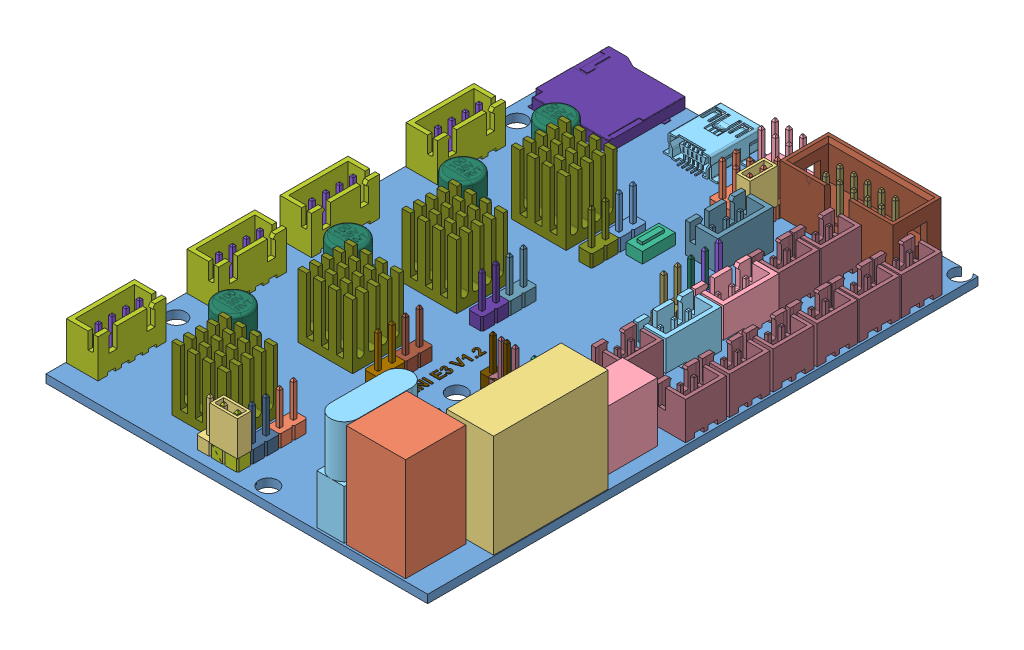
SolidWorks assembly BTT SKR MINI E3 V1.2 - 2020 DR.Phil3D v1.step, configuration Default. Lengths in mm.
Overall size (69.7 22.28 101.21).
95 component instances, 41 part files, 0 mates.
Components (placement in the parent):
- SKR Mini E3 1.2-1: SKR Mini E3 1.2 [SKR Mini E3 1.2] at (0.4313 -1.6126 -0.8701) size (69.7 20.32 100.5)
  - PCB-1: PCB [PCB] at origin size (69.7 1.5 100.5)
  - Power IN-1: Power IN [Power IN] at (-14.6583 0 -3.0665) size (10.79 18.82 11)
  - Power & Bed -1: Power & Bed  [Power & Bed ] at (-15.6583 0 -3.0665) size (8.58 18.82 20.9)
  - E0-1: E0 [E0] at (-15.6583 0 -3.0665) size (6.36 10.82 10)
  - Fuse-1: Fuse [Fuse] at (-14.6583 0 -3.0665) size (5 18.48 14.84)
  - Reset-1: Reset [Reset] at (-4.0633 0 9.9288) size (3 2.5 6)
- 4 pin Header-1: 4 pin Header [4 pin Header] at (-25.3481 -5.4688 -25.9996) x (0 0 1) z (-1 0 0) size (12.4 10.4 5.75)
  - B4B-XH-A (BODY)-1: B4B-XH-A (BODY) [B4B-XH-A (BODY)] at (1.9192 5.3562 13.8157) size (12.4 7 5.75)
  - B4B-XH-A (PIN)-1: B4B-XH-A (PIN) [B4B-XH-A (PIN)] at (5.6692 12.3562 13.2907) x (-1 0 0) z (0 0 1) size (0.64 10.4 0.64)
  - B4B-XH-A (PIN)-2: B4B-XH-A (PIN) [B4B-XH-A (PIN)] at (3.1692 12.3562 13.2907) x (-1 0 0) z (0 0 1) size (0.64 10.4 0.64)
  - B4B-XH-A (PIN)-3: B4B-XH-A (PIN) [B4B-XH-A (PIN)] at (0.6692 12.3562 13.2907) x (-1 0 0) z (0 0 1) size (0.64 10.4 0.64)
  - B4B-XH-A (PIN)-4: B4B-XH-A (PIN) [B4B-XH-A (PIN)] at (-1.8308 12.3562 13.2907) x (-1 0 0) z (0 0 1) size (0.64 10.4 0.64)
- 4 pin Header_1-1: 4 pin Header_1 [4 pin Header_1] at (-25.3481 -5.4688 -2.9996) x (0 0 1) z (-1 0 0) size (12.4 10.4 5.75)
  - B4B-XH-A (BODY)-1: B4B-XH-A (BODY) [B4B-XH-A (BODY)] at (1.9192 5.3562 13.8157) size (12.4 7 5.75)
  - B4B-XH-A (PIN)-1: B4B-XH-A (PIN) [B4B-XH-A (PIN)] at (5.6692 12.3562 13.2907) x (-1 0 0) z (0 0 1) size (0.64 10.4 0.64)
  - B4B-XH-A (PIN)-2: B4B-XH-A (PIN) [B4B-XH-A (PIN)] at (3.1692 12.3562 13.2907) x (-1 0 0) z (0 0 1) size (0.64 10.4 0.64)
  - B4B-XH-A (PIN)-3: B4B-XH-A (PIN) [B4B-XH-A (PIN)] at (0.6692 12.3562 13.2907) x (-1 0 0) z (0 0 1) size (0.64 10.4 0.64)
  - B4B-XH-A (PIN)-4: B4B-XH-A (PIN) [B4B-XH-A (PIN)] at (-1.8308 12.3562 13.2907) x (-1 0 0) z (0 0 1) size (0.64 10.4 0.64)
- 4 pin Header_2-1: 4 pin Header_2 [4 pin Header_2] at (-25.3481 -5.4688 14.0004) x (0 0 1) z (-1 0 0) size (12.4 10.4 5.75)
  - B4B-XH-A (BODY)-1: B4B-XH-A (BODY) [B4B-XH-A (BODY)] at (1.9192 5.3562 13.8157) size (12.4 7 5.75)
  - B4B-XH-A (PIN)-1: B4B-XH-A (PIN) [B4B-XH-A (PIN)] at (5.6692 12.3562 13.2907) x (-1 0 0) z (0 0 1) size (0.64 10.4 0.64)
  - B4B-XH-A (PIN)-2: B4B-XH-A (PIN) [B4B-XH-A (PIN)] at (3.1692 12.3562 13.2907) x (-1 0 0) z (0 0 1) size (0.64 10.4 0.64)
  - B4B-XH-A (PIN)-3: B4B-XH-A (PIN) [B4B-XH-A (PIN)] at (0.6692 12.3562 13.2907) x (-1 0 0) z (0 0 1) size (0.64 10.4 0.64)
  - B4B-XH-A (PIN)-4: B4B-XH-A (PIN) [B4B-XH-A (PIN)] at (-1.8308 12.3562 13.2907) x (-1 0 0) z (0 0 1) size (0.64 10.4 0.64)
- 4 pin Header_3-1: 4 pin Header_3 [4 pin Header_3] at (-25.3481 -5.4688 36.0004) x (0 0 1) z (-1 0 0) size (12.4 10.4 5.75)
  - B4B-XH-A (BODY)-1: B4B-XH-A (BODY) [B4B-XH-A (BODY)] at (1.9192 5.3562 13.8157) size (12.4 7 5.75)
  - B4B-XH-A (PIN)-1: B4B-XH-A (PIN) [B4B-XH-A (PIN)] at (5.6692 12.3562 13.2907) x (-1 0 0) z (0 0 1) size (0.64 10.4 0.64)
  - B4B-XH-A (PIN)-2: B4B-XH-A (PIN) [B4B-XH-A (PIN)] at (3.1692 12.3562 13.2907) x (-1 0 0) z (0 0 1) size (0.64 10.4 0.64)
  - B4B-XH-A (PIN)-3: B4B-XH-A (PIN) [B4B-XH-A (PIN)] at (0.6692 12.3562 13.2907) x (-1 0 0) z (0 0 1) size (0.64 10.4 0.64)
  - B4B-XH-A (PIN)-4: B4B-XH-A (PIN) [B4B-XH-A (PIN)] at (-1.8308 12.3562 13.2907) x (-1 0 0) z (0 0 1) size (0.64 10.4 0.64)
- 2 Pin connector (13)-1: 2 Pin connector (13) [2 Pin connector (13)] at (10.6557 -0.1126 28.8793) x (0 0 -1) z (1 0 0) size (5.08 11.94 2.54)
  - Component52-1: Component52 [Component52] at origin size (5.08 11.94 2.54)
- 2 Pin connector (19)-1: 2 Pin connector (19) [2 Pin connector (19)] at (8.1557 -0.1126 28.8793) x (0 0 -1) z (1 0 0) size (5.08 11.94 2.54)
  - Component53-1: Component53 [Component53] at origin size (5.08 11.94 2.54)
- DS1013-10SSiB v1-1: DS1013-10SSiB v1 [DS1013-10SSiB v1] at (5.7052 0 -46.8226) x (1 0 0) z (0 1 0) size (20.6 9.1 12.4)
  - body-1: body [body] at origin size (20.6 9.1 9.3)
  - pin-1: pin [pin] at origin size (0.64 0.64 11.5)
  - pin-2: pin [pin] at (2.54 0 0) size (0.64 0.64 11.5)
  - pin-3: pin [pin] at (5.08 0 0) size (0.64 0.64 11.5)
  - pin-4: pin [pin] at (7.62 0 0) size (0.64 0.64 11.5)
  - pin-5: pin [pin] at (0 2.54 0) size (0.64 0.64 11.5)
  - pin-6: pin [pin] at (2.54 2.54 0) size (0.64 0.64 11.5)
  - pin-7: pin [pin] at (5.08 2.54 0) size (0.64 0.64 11.5)
  - pin-8: pin [pin] at (7.62 2.54 0) size (0.64 0.64 11.5)
  - pin-9: pin [pin] at (10.16 0 0) size (0.64 0.64 11.5)
  - pin-10: pin [pin] at (10.16 2.54 0) size (0.64 0.64 11.5)
- JST 2pin.step-1: JST 2pin.step [Default] at (9.9082 -0.1126 -7.1947) x (-1 0 0) z (0 0 -1) size (5.73 10.3 7.43)
- Header 3 pin.step-1: Header 3 pin.step [Default] at (1.8482 -0.1126 -33.0477) x (0 0 1) z (-1 0 0) size (10.16 7.2 5.9)
- 100uF 35V 6.3x7.step-1: 100uF 35V 6.3x7.step [Default] at (-28.7944 0.8874 26.9674) x (-1 0 0) z (0 0 -1) size (6.66 7.76 7.2)
- TMC 2209 Heatsink.step-1: TMC 2209 Heatsink.step [Default] at (-21.6787 1.8374 38.0799) x (1 0 0) z (0 1 0) size (9.98 9.3 11.65)
- sdreader.step-1: sdreader.step [Default] at (-33.9687 -1.5126 -38.3866) x (0 0 1) z (0 1 0) size (15 16 2)
- Component14.step-1: Component14.step [Default] at origin size (1.85 0.1 25.79)
- Component15.step-1: Component15.step [Default] at origin size (0.73 0.1 6.6)
- 2 Pin connector.step-1: 2 Pin connector.step [Default] at (-0.9803 -0.3666 -42.1218) x (0 0 1) z (-1 0 0) size (5.08 11.94 2.54)
- Jumper.step-1: Jumper.step [Default] at (-15.4835 0 -3.6239) size (2.55 6.35 5.06)
- Header 3 pin (1).step-1: Header 3 pin (1).step [Default] at (12.9215 -0.1126 -22.9838) x (0 0 1) z (-1 0 0) size (10.16 7.2 5.9)
- Header 3 pin (2).step-1: Header 3 pin (2).step [Default] at (12.9215 -0.1126 -12.4838) x (0 0 1) z (-1 0 0) size (10.16 7.2 5.9)
- 100uF 35V 6.3x7.step-2: 100uF 35V 6.3x7.step [Default] at (-28.7944 0.8874 5.9674) x (-1 0 0) z (0 0 -1) size (6.66 7.76 7.2)
- TMC 2209 Heatsink.step-2: TMC 2209 Heatsink.step [Default] at (-21.6787 1.8374 15.0799) x (1 0 0) z (0 1 0) size (9.98 9.3 11.65)
- 100uF 35V 6.3x7.step-3: 100uF 35V 6.3x7.step [Default] at (-28.7944 0.8874 -15.0326) x (-1 0 0) z (0 0 -1) size (6.66 7.76 7.2)
- TMC 2209 Heatsink.step-3: TMC 2209 Heatsink.step [Default] at (-21.6787 1.8374 -3.9201) x (1 0 0) z (0 1 0) size (9.98 9.3 11.65)
- 100uF 35V 6.3x7.step-4: 100uF 35V 6.3x7.step [Default] at (-28.7944 0.8874 -32.0326) x (-1 0 0) z (0 0 -1) size (6.66 7.76 7.2)
- TMC 2209 Heatsink.step-4: TMC 2209 Heatsink.step [Default] at (-21.6787 1.8374 -23.9201) x (1 0 0) z (0 1 0) size (9.98 9.3 11.65)
- JST 2pin.step-2: JST 2pin.step [Default] at (9.9082 -0.1126 -35.6947) x (-1 0 0) z (0 0 -1) size (5.73 10.3 7.43)
- JST 2pin.step-3: JST 2pin.step [Default] at (9.9082 -0.1126 -43.3829) x (-1 0 0) z (0 0 -1) size (5.73 10.3 7.43)
- JST 2pin.step-4: JST 2pin.step [Default] at (21.4082 -0.1126 -7.1947) x (-1 0 0) z (0 0 -1) size (5.73 10.3 7.43)
- JST 2pin.step-5: JST 2pin.step [Default] at (21.4082 -0.1126 -38.8829) x (-1 0 0) z (0 0 -1) size (5.73 10.3 7.43)
- JST 2pin.step-6: JST 2pin.step [Default] at (21.4082 -0.1126 -15.1947) x (-1 0 0) z (0 0 -1) size (5.73 10.3 7.43)
- JST 2pin.step-7: JST 2pin.step [Default] at (21.4082 -0.1126 -23.1947) x (-1 0 0) z (0 0 -1) size (5.73 10.3 7.43)
- JST 2pin.step-8: JST 2pin.step [Default] at (21.4082 -0.1126 -31.1947) x (-1 0 0) z (0 0 -1) size (5.73 10.3 7.43)
- JST 2pin.step-9: JST 2pin.step [Default] at (21.4082 -0.1126 -46.5829) x (-1 0 0) z (0 0 -1) size (5.73 10.3 7.43)
- 2 Pin connector.step-2: 2 Pin connector.step [Default] at (-3.4803 -0.3666 -42.1218) x (0 0 1) z (-1 0 0) size (5.08 11.94 2.54)
- 2 Pin connector.step-3: 2 Pin connector.step [Default] at (-5.9803 -0.3666 -42.1218) x (0 0 1) z (-1 0 0) size (5.08 11.94 2.54)
- 2 Pin connector.step-4: 2 Pin connector.step [Default] at (-0.9803 -0.3666 -44.6618) x (0 0 1) z (-1 0 0) size (5.08 11.94 2.54)
- Jumper.step-2: Jumper.step [Default] at (-48.7447 0 30.2029) x (0 0 1) z (-1 0 0) size (2.55 6.35 5.06)
- 2 Pin connector (5).step-1: 2 Pin connector (5).step [Default] at (11.0313 -0.1126 9.1899) x (-1 0 0) z (0 0 -1) size (5.08 11.94 2.54)
- 2 Pin connector (11).step-1: 2 Pin connector (11).step [Default] at (-10.2712 -0.3666 44.6158) x (-1 0 0) z (0 0 -1) size (5.08 11.94 2.54)
- 2 Pin connector (12).step-1: 2 Pin connector (12).step [Default] at (6.8963 -0.1126 -23.5114) x (0 0 -1) z (1 0 0) size (5.08 11.94 2.54)
- 2 Pin connector (14).step-1: 2 Pin connector (14).step [Default] at (-10.2606 -0.3666 16.4669) x (0 0 1) z (-1 0 0) size (5.08 11.94 2.54)
- 2 Pin connector (15).step-1: 2 Pin connector (15).step [Default] at (-10.2606 -0.3666 39.4669) x (0 0 1) z (-1 0 0) size (5.08 11.94 2.54)
- 2 Pin connector (16).step-1: 2 Pin connector (16).step [Default] at (-10.2606 -0.3666 11.4669) x (0 0 1) z (-1 0 0) size (5.08 11.94 2.54)
- 2 Pin connector (17).step-1: 2 Pin connector (17).step [Default] at (6.8963 -0.1126 -16.0114) x (0 0 -1) z (1 0 0) size (5.08 11.94 2.54)
- 2 Pin connector (18).step-1: 2 Pin connector (18).step [Default] at (5.0143 -0.1126 9.2211) x (-1 0 0) z (0 0 -1) size (5.08 11.94 2.54)
- 2 Pin connector (20).step-1: 2 Pin connector (20).step [Default] at (-10.2606 -0.3666 -7.5331) x (0 0 1) z (-1 0 0) size (5.08 11.94 2.54)
- 2 Pin connector (21).step-1: 2 Pin connector (21).step [Default] at (6.8963 -0.1126 -21.0114) x (0 0 -1) z (1 0 0) size (5.08 11.94 2.54)
- 2 Pin connector (22).step-1: 2 Pin connector (22).step [Default] at (-10.2606 -0.3666 -22.5331) x (0 0 1) z (-1 0 0) size (5.08 11.94 2.54)
- 2 Pin connector (23).step-1: 2 Pin connector (23).step [Default] at (-10.2606 -0.3666 -2.5331) x (0 0 1) z (-1 0 0) size (5.08 11.94 2.54)
- 2 Pin connector (24).step-1: 2 Pin connector (24).step [Default] at (3.4513 -0.1126 9.1899) x (-1 0 0) z (0 0 -1) size (5.08 11.94 2.54)
- 2 Pin connector (25).step-1: 2 Pin connector (25).step [Default] at (-10.2606 -0.3666 -27.5331) x (0 0 1) z (-1 0 0) size (5.08 11.94 2.54)
- 2 Pin connector (26).step-1: 2 Pin connector (26).step [Default] at (-10.2606 -0.3666 34.4669) x (0 0 1) z (-1 0 0) size (5.08 11.94 2.54)
- 2 Pin connector (27).step-1: 2 Pin connector (27).step [Default] at (-12.7712 -0.3666 44.6158) x (-1 0 0) z (0 0 -1) size (5.08 11.94 2.54)
- zl201-3_p2-54_l7-62_w2-54_h8-89 v1.step-1: zl201-3_p2-54_l7-62_w2-54_h8-89 v1.step [Default] at (-7.1165 -0.1 -47.85) size (7.62 11.94 2.54)
- zl201-3_p2-54_l7-62_w2-54_h8-89 v1.step-2: zl201-3_p2-54_l7-62_w2-54_h8-89 v1.step [Default] at (-7.1165 -0.1 -50.35) size (7.62 11.94 2.54)
- USB_MINI_B_SMD v35 v1.step-1: USB_MINI_B_SMD v35 v1.step [Default] at (-15.7973 -0.1 -52.75) x (-1 0 0) z (0 0 -1) size (9.9 4.19 9.9)
